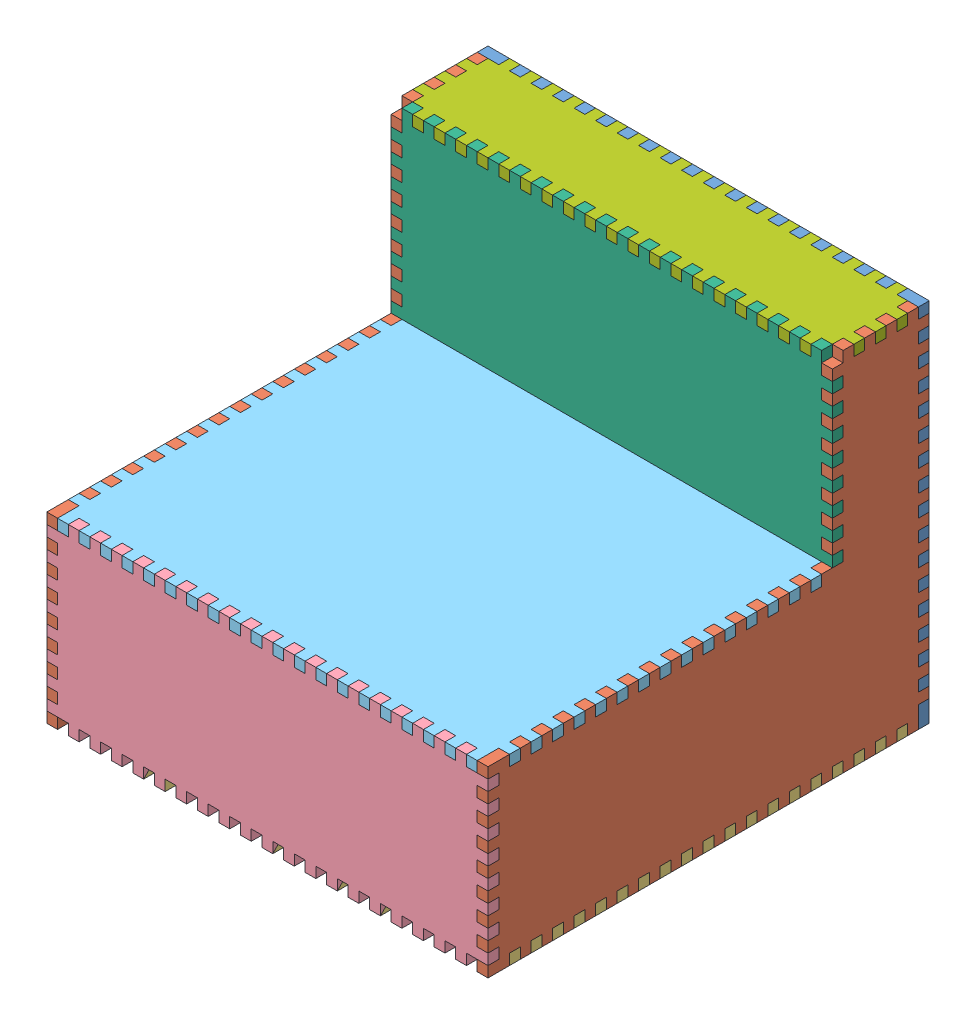
SolidWorks assembly Asemble Box, configuration Default. Lengths in mm.
Overall size (260.35 215.9 260.35).
8 component instances, 7 part files, 19 mates.
Components (placement in the parent):
- Back-1: Back [Default] at (-43.9016 293.9439 166.8921) size (260.35 215.9 6.35)
- Side-2: Side [Default] at (-174.0766 239.9689 297.0671) size (6.35 215.9 260.35)
- Bottom_4sided-1: Bottom_4sided [Default] at (-43.9016 185.9939 297.0671) size (260.35 6.35 260.35)
- Side-4: Side [Default] at (79.9234 239.9689 297.0671) size (6.35 215.9 260.35)
- Front-1: Front [Default] at (-43.9016 239.9689 420.8921) size (260.35 107.95 6.35)
- Top_big-2: Top_big [Default] at (-43.9016 287.5939 325.6421) size (260.35 6.35 203.2)
- Front_topversion-1: Front_topversion [Default] at (-43.9016 347.9189 217.6921) size (260.35 107.95 6.35)
- Top-small-1: Top-small [Default] at (-43.9016 395.5439 195.4671) size (260.35 6.35 57.15)
Mates (geometry in assembly coordinates):
- Coincident1: coincident aligned: line of Back-1 through (-174.0766 198.6939 173.2421) axis (0 -1 0); line of ? through (-174.0766 215.7779 173.2421) axis (0 -1 0)
- Coincident4: coincident aligned: line of Back-1 through (-174.0766 198.6939 166.8921) axis (1 0 0); line of Side-2 through (-174.0766 198.6939 166.8921) axis (1 0 0)
- Coincident6: coincident aligned: line of Back-1 through (-174.0766 198.6939 173.2421) axis (0 -1 0); line of Side-2 through (-174.0766 198.6939 173.2421) axis (0 -1 0)
- Coincident10: coincident: line of Side-2 through (-174.0766 192.3439 179.5921) axis (0 0 1); plane of Bottom_4sided-1 through (-43.9016 192.3439 297.0671) normal (0 1 0)
- Coincident11: coincident anti-aligned: line of Back-1 through (-161.3766 192.3439 166.8921) axis (1 0 0); line of Bottom_4sided-1 through (-155.0266 192.3439 166.8921) axis (-1 0 0)
- Coincident12: coincident aligned: line of Side-2 through (-174.0766 192.3439 179.5921) axis (0 0 1); line of Bottom_4sided-1 through (-174.0766 192.3439 179.5921) axis (0 0 1)
- Coincident13: coincident anti-aligned: line of Back-1 through (86.2734 185.9939 173.2421) axis (0 1 0); line of Side-4 through (86.2734 198.6939 173.2421) axis (0 -1 0)
- Coincident14: coincident anti-aligned: line of Back-1 through (86.2734 401.8939 173.2421) axis (-1 0 0); line of Side-4 through (79.9234 401.8939 173.2421) axis (1 0 0)
- Coincident15: coincident aligned: line of Side-4 through (86.2734 192.3439 420.8921) axis (0 1 0); line of Front-1 through (86.2734 192.3439 420.8921) axis (0 1 0)
- Coincident16: coincident anti-aligned: line of Side-4 through (79.9234 287.5939 427.2421) axis (1 0 0); line of Front-1 through (86.2734 287.5939 427.2421) axis (-1 0 0)
- Coincident17: coincident aligned: line of Side-4 through (86.2734 293.9439 414.5421) axis (0 0 1); line of ? through (86.2734 293.9439 385.4709) axis (0 0 1)
- Parallel2: parallel: line of Front-1 through (67.2234 287.5939 427.2421) axis (-1 0 0); plane of ? through (-37.5516 300.2939 299.7459) normal (0 1 0)
- Coincident27: coincident anti-aligned: line of Front-1 through (86.2734 287.5939 427.2421) axis (-1 0 0); line of Top_big-2 through (73.5734 287.5939 427.2421) axis (1 0 0)
- Coincident28: coincident aligned: line of Side-4 through (86.2734 287.5939 414.5421) axis (0 0 -1); line of Top_big-2 through (86.2734 287.5939 414.5421) axis (0 0 -1)
- Coincident30: coincident anti-aligned: line of Side-4 through (86.2734 293.9439 217.6921) axis (0 0 1); line of Front_topversion-1 through (86.2734 293.9439 224.0421) axis (0 0 -1)
- Coincident31: coincident aligned: line of Side-2 through (-174.0766 300.2939 217.6921) axis (0 0 1); line of Front_topversion-1 through (-174.0766 300.2939 217.6921) axis (0 0 1)
- Coincident32: coincident aligned: line of Side-2 through (-174.0766 306.6439 224.0421) axis (0 -1 0); line of Front_topversion-1 through (-174.0766 300.2939 224.0421) axis (0 -1 0)
- Coincident33: coincident aligned: line of Front_topversion-1 through (67.2234 395.5439 224.0421) axis (1 0 0); line of Top-small-1 through (67.2234 395.5439 224.0421) axis (1 0 0)
- Coincident34: coincident aligned: line of Side-4 through (86.2734 395.5439 211.3421) axis (0 0 -1); line of Top-small-1 through (86.2734 395.5439 211.3421) axis (0 0 -1)
